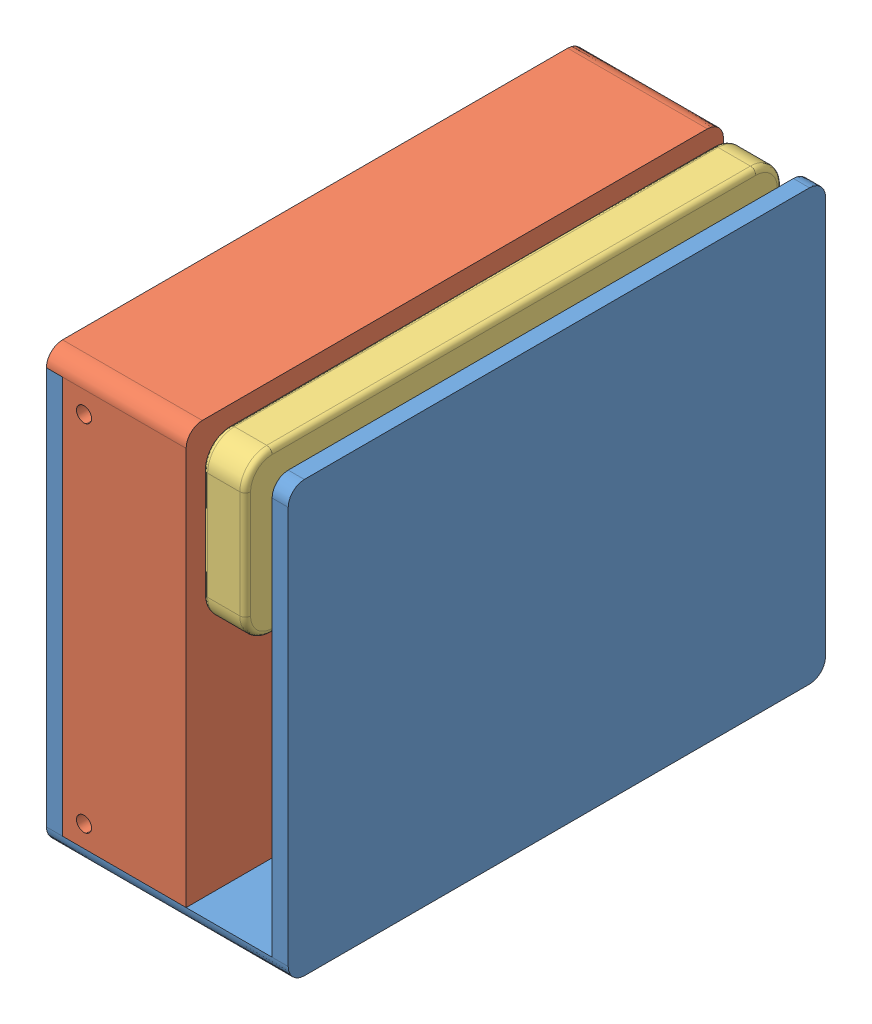
SolidWorks assembly weathercube, configuration ﾃﾞﾌｫﾙﾄ. Lengths in mm.
Overall size (45 80 100).
3 component instances, 3 part files, 7 mates.
Components (placement in the parent):
- weathercubecase1-1: weathercubecase1 [ﾃﾞﾌｫﾙﾄ] at (21.6572 -34.6163 50) size (45 80 100)
- weathercubecase2-1: weathercubecase2 [ﾃﾞﾌｫﾙﾄ] at (2.6572 -31.6163 150) x (0 0 1) z (-1 0 0) size (100 77 26)
- weathercubebar-1: weathercubebar [ﾃﾞﾌｫﾙﾄ] at (5.6572 45.3837 150) x (0 -1 0) z (1 0 0) size (30 100 8)
Mates (geometry in assembly coordinates):
- Coincident5: coincident anti-aligned: plane of weathercube1-1 through (-23.3428 42.3837 150) normal (0 1 0); plane of weathercube2-1 through (-20.3428 42.3837 147) normal (0 -1 0)
- Coincident7: coincident anti-aligned: plane of weathercube1-1 through (-20.3428 42.3837 150) normal (1 0 0); plane of weathercube2-1 through (-20.3428 -31.6163 150) normal (-1 0 0)
- Coincident8: coincident aligned: plane of weathercube1-1 through (21.6572 -34.6163 150) normal (0 0 1); plane of weathercube2-1 through (-0.3428 -31.6163 150) normal (0 0 1)
- Parallel1: parallel: plane of weathercubecase2-1 through (2.6572 -31.6163 150) normal (1 0 0); plane of weathercubebar-1 through (14.8904 20.3837 145) normal (1 0 0)
- Coincident11: coincident: plane of weathercubecase2-1 through (-0.3428 -31.6163 150) normal (0 0 1); plane of weathercubebar-1 through (14.8904 40.3837 150) normal (0 0 1)
- Coincident12: coincident: plane of weathercubecase2-1 through (-0.3428 45.3837 150) normal (0 1 0); plane of weathercubebar-1 through (14.8904 45.3837 145) normal (0 1 0)
- Distance1: distance = 3 mm anti-aligned: plane of weathercubebar-1 through (5.6572 20.3837 145) normal (-1 0 0); plane of weathercubecase2-1 through (2.6572 -31.6163 150) normal (1 0 0)
